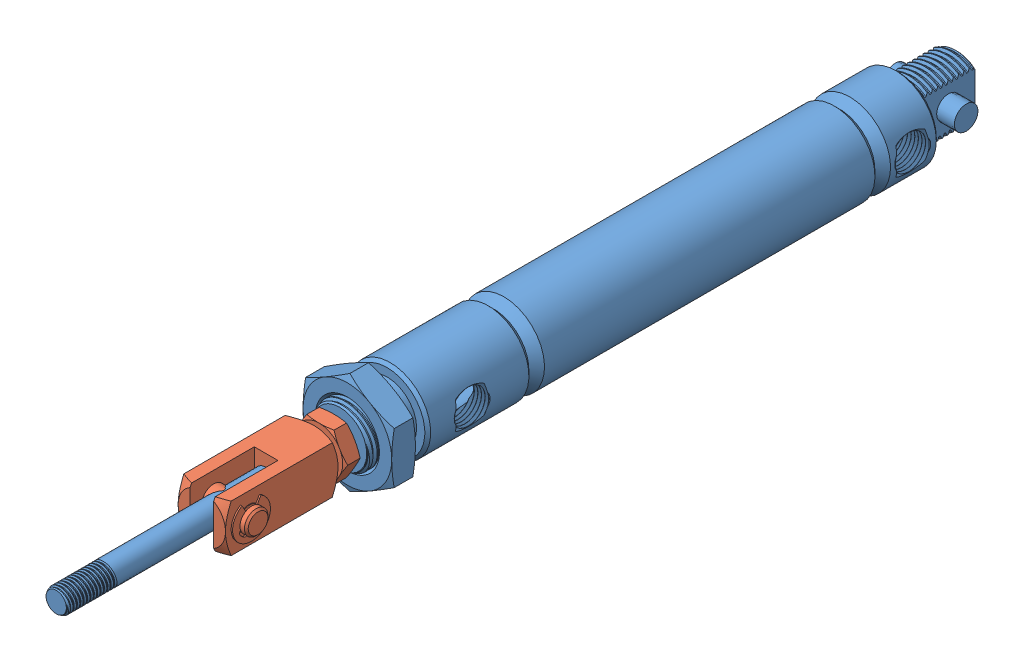
SolidWorks assembly 2in .75 bore piston, configuration Default. Lengths in mm.
Overall size (23.81 27.5 242.22).
2 component instances, 2 part files, 3 mates.
Components (placement in the parent):
- 6498K443-1: 6498K443 [6498K443] at (-85.1093 26.2433 -4.6888) size (23.81 27.5 242.22)
- .75 bore Clevis-1: .75 bore Clevis [6498K42] at (-85.1093 26.2433 78.7502) x (1 0 0) z (0 -1 0) size (20.16 35.74 12.7)
Mates (geometry in assembly coordinates):
- LimitDistance1: limit distance = 1.524 mm anti-aligned: plane of .75 bore Clevis-1 through (-85.1093 13.5433 73.4162) normal (0 0 -1); plane of 6498K443-1 through (-85.1093 26.2433 71.8922) normal (0 0 1)
- Concentric1: concentric aligned: cylinder of 6498K443-1 through (-85.1093 26.2433 7.5032) axis (0 0 -1) radius 3.175; circle of .75 bore Clevis-1
- Parallel1: parallel aligned: plane of 6498K443-1 through (-80.3468 34.1808 -47.0208) normal (1 0 0); plane of .75 bore Clevis-1 through (-78.7593 19.8933 82.4764) normal (1 0 0)
